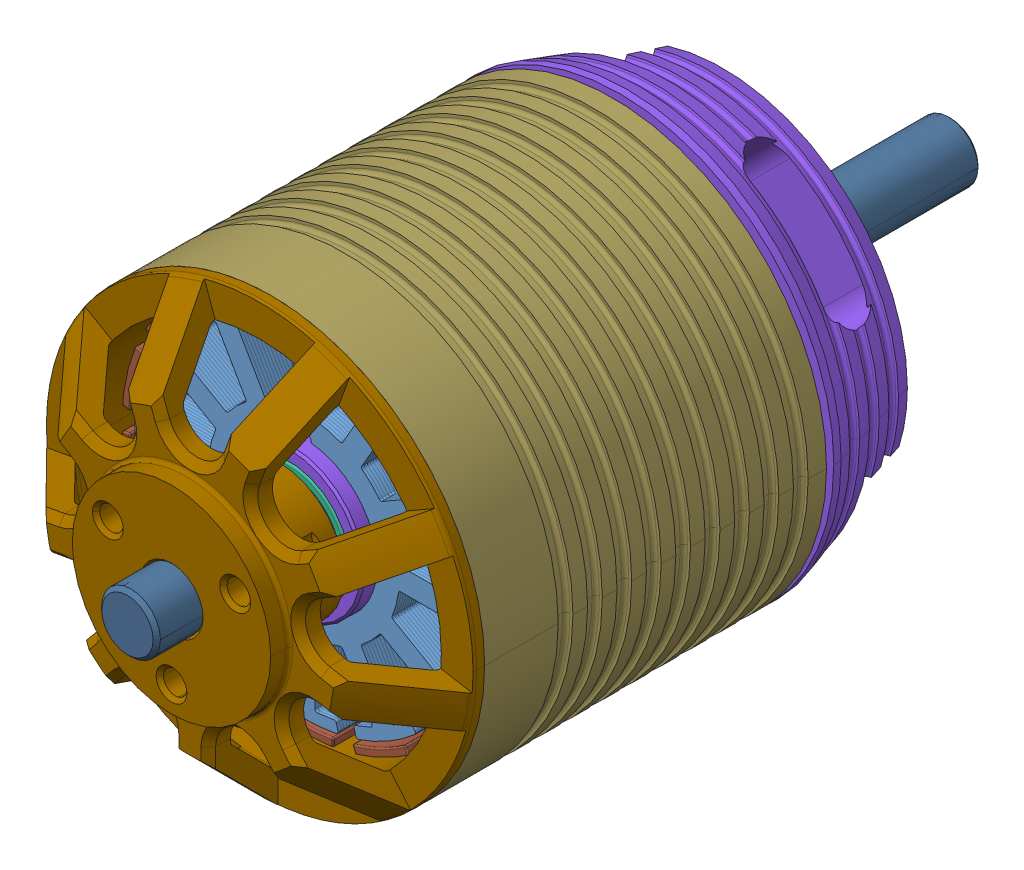
SolidWorks assembly BA-2320-Motor, configuration Default. Lengths in mm.
Overall size (29.1 29.1 56).
158 component instances, 15 part files, 0 mates.
Components (placement in the parent):
- 2320-Stator-Assem.STEP-1: 2320-Stator-Assem.STEP [Default] at (54.7125 -14.0588 -19.3197) size (29.1 29.1 29.5)
  - 23x10x20mm-Stator.STEP-1: 23x10x20mm-Stator.STEP [Default] at (-19.0817 6.8885 -13.7) size (23 23 20)
    - 23x10x15mm-Stator.STEP-1: 23x10x15mm-Stator.STEP [Default] at (56.8774 -9.8625 7.0262) size (23 23 15)
      - 23x10x5mm-Stator.STEP-1: 23x10x5mm-Stator.STEP [Default] at (-13.8317 15.0051 -0.8954) size (23 23 5)
        - 23x10x1mm-Stator.STEP-1: 23x10x1mm-Stator.STEP [Default] at (-15.1244 2.7036 6.5442) size (23 23 1)
          - 23x10-Stator-Plate.STEP-1: 23x10-Stator-Plate.STEP [Default] at (-25.8459 0.0676 13.4926) size (23 23 0.2)
          - 23x10-Stator-Plate.STEP-2: 23x10-Stator-Plate.STEP [Default] at (-25.8459 0.0676 13.2926) size (23 23 0.2)
          - 23x10-Stator-Plate.STEP-3: 23x10-Stator-Plate.STEP [Default] at (-25.8459 0.0676 13.0926) size (23 23 0.2)
          - 23x10-Stator-Plate.STEP-4: 23x10-Stator-Plate.STEP [Default] at (-25.8459 0.0676 12.8926) size (23 23 0.2)
          - 23x10-Stator-Plate.STEP-5: 23x10-Stator-Plate.STEP [Default] at (-25.8459 0.0676 12.6926) size (23 23 0.2)
        - 23x10x1mm-Stator.STEP-2: 23x10x1mm-Stator.STEP [Default] at (-15.1244 2.7036 5.5442) size (23 23 1)
          - 23x10-Stator-Plate.STEP-1: 23x10-Stator-Plate.STEP [Default] at (-25.8459 0.0676 13.4926) size (23 23 0.2)
          - 23x10-Stator-Plate.STEP-2: 23x10-Stator-Plate.STEP [Default] at (-25.8459 0.0676 13.2926) size (23 23 0.2)
          - 23x10-Stator-Plate.STEP-3: 23x10-Stator-Plate.STEP [Default] at (-25.8459 0.0676 13.0926) size (23 23 0.2)
          - 23x10-Stator-Plate.STEP-4: 23x10-Stator-Plate.STEP [Default] at (-25.8459 0.0676 12.8926) size (23 23 0.2)
          - 23x10-Stator-Plate.STEP-5: 23x10-Stator-Plate.STEP [Default] at (-25.8459 0.0676 12.6926) size (23 23 0.2)
        - 23x10x1mm-Stator.STEP-3: 23x10x1mm-Stator.STEP [Default] at (-15.1244 2.7036 4.5442) size (23 23 1)
          - 23x10-Stator-Plate.STEP-1: 23x10-Stator-Plate.STEP [Default] at (-25.8459 0.0676 13.4926) size (23 23 0.2)
          - 23x10-Stator-Plate.STEP-2: 23x10-Stator-Plate.STEP [Default] at (-25.8459 0.0676 13.2926) size (23 23 0.2)
          - 23x10-Stator-Plate.STEP-3: 23x10-Stator-Plate.STEP [Default] at (-25.8459 0.0676 13.0926) size (23 23 0.2)
          - 23x10-Stator-Plate.STEP-4: 23x10-Stator-Plate.STEP [Default] at (-25.8459 0.0676 12.8926) size (23 23 0.2)
          - 23x10-Stator-Plate.STEP-5: 23x10-Stator-Plate.STEP [Default] at (-25.8459 0.0676 12.6926) size (23 23 0.2)
        - 23x10x1mm-Stator.STEP-4: 23x10x1mm-Stator.STEP [Default] at (-15.1244 2.7036 3.5442) size (23 23 1)
          - 23x10-Stator-Plate.STEP-1: 23x10-Stator-Plate.STEP [Default] at (-25.8459 0.0676 13.4926) size (23 23 0.2)
          - 23x10-Stator-Plate.STEP-2: 23x10-Stator-Plate.STEP [Default] at (-25.8459 0.0676 13.2926) size (23 23 0.2)
          - 23x10-Stator-Plate.STEP-3: 23x10-Stator-Plate.STEP [Default] at (-25.8459 0.0676 13.0926) size (23 23 0.2)
          - 23x10-Stator-Plate.STEP-4: 23x10-Stator-Plate.STEP [Default] at (-25.8459 0.0676 12.8926) size (23 23 0.2)
          - 23x10-Stator-Plate.STEP-5: 23x10-Stator-Plate.STEP [Default] at (-25.8459 0.0676 12.6926) size (23 23 0.2)
        - 23x10x1mm-Stator.STEP-5: 23x10x1mm-Stator.STEP [Default] at (-15.1244 2.7036 2.5442) size (23 23 1)
          - 23x10-Stator-Plate.STEP-1: 23x10-Stator-Plate.STEP [Default] at (-25.8459 0.0676 13.4926) size (23 23 0.2)
          - 23x10-Stator-Plate.STEP-2: 23x10-Stator-Plate.STEP [Default] at (-25.8459 0.0676 13.2926) size (23 23 0.2)
          - 23x10-Stator-Plate.STEP-3: 23x10-Stator-Plate.STEP [Default] at (-25.8459 0.0676 13.0926) size (23 23 0.2)
          - 23x10-Stator-Plate.STEP-4: 23x10-Stator-Plate.STEP [Default] at (-25.8459 0.0676 12.8926) size (23 23 0.2)
          - 23x10-Stator-Plate.STEP-5: 23x10-Stator-Plate.STEP [Default] at (-25.8459 0.0676 12.6926) size (23 23 0.2)
      - 23x10x5mm-Stator.STEP-2: 23x10x5mm-Stator.STEP [Default] at (-13.8317 15.0051 -5.8954) size (23 23 5)
        - 23x10x1mm-Stator.STEP-1: 23x10x1mm-Stator.STEP [Default] at (-15.1244 2.7036 6.5442) size (23 23 1)
          - 23x10-Stator-Plate.STEP-1: 23x10-Stator-Plate.STEP [Default] at (-25.8459 0.0676 13.4926) size (23 23 0.2)
          - 23x10-Stator-Plate.STEP-2: 23x10-Stator-Plate.STEP [Default] at (-25.8459 0.0676 13.2926) size (23 23 0.2)
          - 23x10-Stator-Plate.STEP-3: 23x10-Stator-Plate.STEP [Default] at (-25.8459 0.0676 13.0926) size (23 23 0.2)
          - 23x10-Stator-Plate.STEP-4: 23x10-Stator-Plate.STEP [Default] at (-25.8459 0.0676 12.8926) size (23 23 0.2)
          - 23x10-Stator-Plate.STEP-5: 23x10-Stator-Plate.STEP [Default] at (-25.8459 0.0676 12.6926) size (23 23 0.2)
        - 23x10x1mm-Stator.STEP-2: 23x10x1mm-Stator.STEP [Default] at (-15.1244 2.7036 5.5442) size (23 23 1)
          - 23x10-Stator-Plate.STEP-1: 23x10-Stator-Plate.STEP [Default] at (-25.8459 0.0676 13.4926) size (23 23 0.2)
          - 23x10-Stator-Plate.STEP-2: 23x10-Stator-Plate.STEP [Default] at (-25.8459 0.0676 13.2926) size (23 23 0.2)
          - 23x10-Stator-Plate.STEP-3: 23x10-Stator-Plate.STEP [Default] at (-25.8459 0.0676 13.0926) size (23 23 0.2)
          - 23x10-Stator-Plate.STEP-4: 23x10-Stator-Plate.STEP [Default] at (-25.8459 0.0676 12.8926) size (23 23 0.2)
          - 23x10-Stator-Plate.STEP-5: 23x10-Stator-Plate.STEP [Default] at (-25.8459 0.0676 12.6926) size (23 23 0.2)
        - 23x10x1mm-Stator.STEP-3: 23x10x1mm-Stator.STEP [Default] at (-15.1244 2.7036 4.5442) size (23 23 1)
          - 23x10-Stator-Plate.STEP-1: 23x10-Stator-Plate.STEP [Default] at (-25.8459 0.0676 13.4926) size (23 23 0.2)
          - 23x10-Stator-Plate.STEP-2: 23x10-Stator-Plate.STEP [Default] at (-25.8459 0.0676 13.2926) size (23 23 0.2)
          - 23x10-Stator-Plate.STEP-3: 23x10-Stator-Plate.STEP [Default] at (-25.8459 0.0676 13.0926) size (23 23 0.2)
          - 23x10-Stator-Plate.STEP-4: 23x10-Stator-Plate.STEP [Default] at (-25.8459 0.0676 12.8926) size (23 23 0.2)
          - 23x10-Stator-Plate.STEP-5: 23x10-Stator-Plate.STEP [Default] at (-25.8459 0.0676 12.6926) size (23 23 0.2)
        - 23x10x1mm-Stator.STEP-4: 23x10x1mm-Stator.STEP [Default] at (-15.1244 2.7036 3.5442) size (23 23 1)
          - 23x10-Stator-Plate.STEP-1: 23x10-Stator-Plate.STEP [Default] at (-25.8459 0.0676 13.4926) size (23 23 0.2)
          - 23x10-Stator-Plate.STEP-2: 23x10-Stator-Plate.STEP [Default] at (-25.8459 0.0676 13.2926) size (23 23 0.2)
          - 23x10-Stator-Plate.STEP-3: 23x10-Stator-Plate.STEP [Default] at (-25.8459 0.0676 13.0926) size (23 23 0.2)
          - 23x10-Stator-Plate.STEP-4: 23x10-Stator-Plate.STEP [Default] at (-25.8459 0.0676 12.8926) size (23 23 0.2)
          - 23x10-Stator-Plate.STEP-5: 23x10-Stator-Plate.STEP [Default] at (-25.8459 0.0676 12.6926) size (23 23 0.2)
        - 23x10x1mm-Stator.STEP-5: 23x10x1mm-Stator.STEP [Default] at (-15.1244 2.7036 2.5442) size (23 23 1)
          - 23x10-Stator-Plate.STEP-1: 23x10-Stator-Plate.STEP [Default] at (-25.8459 0.0676 13.4926) size (23 23 0.2)
          - 23x10-Stator-Plate.STEP-2: 23x10-Stator-Plate.STEP [Default] at (-25.8459 0.0676 13.2926) size (23 23 0.2)
          - 23x10-Stator-Plate.STEP-3: 23x10-Stator-Plate.STEP [Default] at (-25.8459 0.0676 13.0926) size (23 23 0.2)
          - 23x10-Stator-Plate.STEP-4: 23x10-Stator-Plate.STEP [Default] at (-25.8459 0.0676 12.8926) size (23 23 0.2)
          - 23x10-Stator-Plate.STEP-5: 23x10-Stator-Plate.STEP [Default] at (-25.8459 0.0676 12.6926) size (23 23 0.2)
      - 23x10x5mm-Stator.STEP-3: 23x10x5mm-Stator.STEP [Default] at (-13.8317 15.0051 -10.8954) size (23 23 5)
        - 23x10x1mm-Stator.STEP-1: 23x10x1mm-Stator.STEP [Default] at (-15.1244 2.7036 6.5442) size (23 23 1)
          - 23x10-Stator-Plate.STEP-1: 23x10-Stator-Plate.STEP [Default] at (-25.8459 0.0676 13.4926) size (23 23 0.2)
          - 23x10-Stator-Plate.STEP-2: 23x10-Stator-Plate.STEP [Default] at (-25.8459 0.0676 13.2926) size (23 23 0.2)
          - 23x10-Stator-Plate.STEP-3: 23x10-Stator-Plate.STEP [Default] at (-25.8459 0.0676 13.0926) size (23 23 0.2)
          - 23x10-Stator-Plate.STEP-4: 23x10-Stator-Plate.STEP [Default] at (-25.8459 0.0676 12.8926) size (23 23 0.2)
          - 23x10-Stator-Plate.STEP-5: 23x10-Stator-Plate.STEP [Default] at (-25.8459 0.0676 12.6926) size (23 23 0.2)
        - 23x10x1mm-Stator.STEP-2: 23x10x1mm-Stator.STEP [Default] at (-15.1244 2.7036 5.5442) size (23 23 1)
          - 23x10-Stator-Plate.STEP-1: 23x10-Stator-Plate.STEP [Default] at (-25.8459 0.0676 13.4926) size (23 23 0.2)
          - 23x10-Stator-Plate.STEP-2: 23x10-Stator-Plate.STEP [Default] at (-25.8459 0.0676 13.2926) size (23 23 0.2)
          - 23x10-Stator-Plate.STEP-3: 23x10-Stator-Plate.STEP [Default] at (-25.8459 0.0676 13.0926) size (23 23 0.2)
          - 23x10-Stator-Plate.STEP-4: 23x10-Stator-Plate.STEP [Default] at (-25.8459 0.0676 12.8926) size (23 23 0.2)
          - 23x10-Stator-Plate.STEP-5: 23x10-Stator-Plate.STEP [Default] at (-25.8459 0.0676 12.6926) size (23 23 0.2)
        - 23x10x1mm-Stator.STEP-3: 23x10x1mm-Stator.STEP [Default] at (-15.1244 2.7036 4.5442) size (23 23 1)
          - 23x10-Stator-Plate.STEP-1: 23x10-Stator-Plate.STEP [Default] at (-25.8459 0.0676 13.4926) size (23 23 0.2)
          - 23x10-Stator-Plate.STEP-2: 23x10-Stator-Plate.STEP [Default] at (-25.8459 0.0676 13.2926) size (23 23 0.2)
          - 23x10-Stator-Plate.STEP-3: 23x10-Stator-Plate.STEP [Default] at (-25.8459 0.0676 13.0926) size (23 23 0.2)
          - 23x10-Stator-Plate.STEP-4: 23x10-Stator-Plate.STEP [Default] at (-25.8459 0.0676 12.8926) size (23 23 0.2)
          - 23x10-Stator-Plate.STEP-5: 23x10-Stator-Plate.STEP [Default] at (-25.8459 0.0676 12.6926) size (23 23 0.2)
        - 23x10x1mm-Stator.STEP-4: 23x10x1mm-Stator.STEP [Default] at (-15.1244 2.7036 3.5442) size (23 23 1)
          - 23x10-Stator-Plate.STEP-1: 23x10-Stator-Plate.STEP [Default] at (-25.8459 0.0676 13.4926) size (23 23 0.2)
          - 23x10-Stator-Plate.STEP-2: 23x10-Stator-Plate.STEP [Default] at (-25.8459 0.0676 13.2926) size (23 23 0.2)
          - 23x10-Stator-Plate.STEP-3: 23x10-Stator-Plate.STEP [Default] at (-25.8459 0.0676 13.0926) size (23 23 0.2)
          - 23x10-Stator-Plate.STEP-4: 23x10-Stator-Plate.STEP [Default] at (-25.8459 0.0676 12.8926) size (23 23 0.2)
          - 23x10-Stator-Plate.STEP-5: 23x10-Stator-Plate.STEP [Default] at (-25.8459 0.0676 12.6926) size (23 23 0.2)
        - 23x10x1mm-Stator.STEP-5: 23x10x1mm-Stator.STEP [Default] at (-15.1244 2.7036 2.5442) size (23 23 1)
          - 23x10-Stator-Plate.STEP-1: 23x10-Stator-Plate.STEP [Default] at (-25.8459 0.0676 13.4926) size (23 23 0.2)
          - 23x10-Stator-Plate.STEP-2: 23x10-Stator-Plate.STEP [Default] at (-25.8459 0.0676 13.2926) size (23 23 0.2)
          - 23x10-Stator-Plate.STEP-3: 23x10-Stator-Plate.STEP [Default] at (-25.8459 0.0676 13.0926) size (23 23 0.2)
          - 23x10-Stator-Plate.STEP-4: 23x10-Stator-Plate.STEP [Default] at (-25.8459 0.0676 12.8926) size (23 23 0.2)
          - 23x10-Stator-Plate.STEP-5: 23x10-Stator-Plate.STEP [Default] at (-25.8459 0.0676 12.6926) size (23 23 0.2)
    - 23x10x5mm-Stator.STEP-1: 23x10x5mm-Stator.STEP [Default] at (43.0457 5.1426 -8.8692) size (23 23 5)
      - 23x10x1mm-Stator.STEP-1: 23x10x1mm-Stator.STEP [Default] at (-15.1244 2.7036 6.5442) size (23 23 1)
        - 23x10-Stator-Plate.STEP-1: 23x10-Stator-Plate.STEP [Default] at (-25.8459 0.0676 13.4926) size (23 23 0.2)
        - 23x10-Stator-Plate.STEP-2: 23x10-Stator-Plate.STEP [Default] at (-25.8459 0.0676 13.2926) size (23 23 0.2)
        - 23x10-Stator-Plate.STEP-3: 23x10-Stator-Plate.STEP [Default] at (-25.8459 0.0676 13.0926) size (23 23 0.2)
        - 23x10-Stator-Plate.STEP-4: 23x10-Stator-Plate.STEP [Default] at (-25.8459 0.0676 12.8926) size (23 23 0.2)
        - 23x10-Stator-Plate.STEP-5: 23x10-Stator-Plate.STEP [Default] at (-25.8459 0.0676 12.6926) size (23 23 0.2)
      - 23x10x1mm-Stator.STEP-2: 23x10x1mm-Stator.STEP [Default] at (-15.1244 2.7036 5.5442) size (23 23 1)
        - 23x10-Stator-Plate.STEP-1: 23x10-Stator-Plate.STEP [Default] at (-25.8459 0.0676 13.4926) size (23 23 0.2)
        - 23x10-Stator-Plate.STEP-2: 23x10-Stator-Plate.STEP [Default] at (-25.8459 0.0676 13.2926) size (23 23 0.2)
        - 23x10-Stator-Plate.STEP-3: 23x10-Stator-Plate.STEP [Default] at (-25.8459 0.0676 13.0926) size (23 23 0.2)
        - 23x10-Stator-Plate.STEP-4: 23x10-Stator-Plate.STEP [Default] at (-25.8459 0.0676 12.8926) size (23 23 0.2)
        - 23x10-Stator-Plate.STEP-5: 23x10-Stator-Plate.STEP [Default] at (-25.8459 0.0676 12.6926) size (23 23 0.2)
      - 23x10x1mm-Stator.STEP-3: 23x10x1mm-Stator.STEP [Default] at (-15.1244 2.7036 4.5442) size (23 23 1)
        - 23x10-Stator-Plate.STEP-1: 23x10-Stator-Plate.STEP [Default] at (-25.8459 0.0676 13.4926) size (23 23 0.2)
        - 23x10-Stator-Plate.STEP-2: 23x10-Stator-Plate.STEP [Default] at (-25.8459 0.0676 13.2926) size (23 23 0.2)
        - 23x10-Stator-Plate.STEP-3: 23x10-Stator-Plate.STEP [Default] at (-25.8459 0.0676 13.0926) size (23 23 0.2)
        - 23x10-Stator-Plate.STEP-4: 23x10-Stator-Plate.STEP [Default] at (-25.8459 0.0676 12.8926) size (23 23 0.2)
        - 23x10-Stator-Plate.STEP-5: 23x10-Stator-Plate.STEP [Default] at (-25.8459 0.0676 12.6926) size (23 23 0.2)
      - 23x10x1mm-Stator.STEP-4: 23x10x1mm-Stator.STEP [Default] at (-15.1244 2.7036 3.5442) size (23 23 1)
        - 23x10-Stator-Plate.STEP-1: 23x10-Stator-Plate.STEP [Default] at (-25.8459 0.0676 13.4926) size (23 23 0.2)
        - 23x10-Stator-Plate.STEP-2: 23x10-Stator-Plate.STEP [Default] at (-25.8459 0.0676 13.2926) size (23 23 0.2)
        - 23x10-Stator-Plate.STEP-3: 23x10-Stator-Plate.STEP [Default] at (-25.8459 0.0676 13.0926) size (23 23 0.2)
        - 23x10-Stator-Plate.STEP-4: 23x10-Stator-Plate.STEP [Default] at (-25.8459 0.0676 12.8926) size (23 23 0.2)
        - 23x10-Stator-Plate.STEP-5: 23x10-Stator-Plate.STEP [Default] at (-25.8459 0.0676 12.6926) size (23 23 0.2)
      - 23x10x1mm-Stator.STEP-5: 23x10x1mm-Stator.STEP [Default] at (-15.1244 2.7036 2.5442) size (23 23 1)
        - 23x10-Stator-Plate.STEP-1: 23x10-Stator-Plate.STEP [Default] at (-25.8459 0.0676 13.4926) size (23 23 0.2)
        - 23x10-Stator-Plate.STEP-2: 23x10-Stator-Plate.STEP [Default] at (-25.8459 0.0676 13.2926) size (23 23 0.2)
        - 23x10-Stator-Plate.STEP-3: 23x10-Stator-Plate.STEP [Default] at (-25.8459 0.0676 13.0926) size (23 23 0.2)
        - 23x10-Stator-Plate.STEP-4: 23x10-Stator-Plate.STEP [Default] at (-25.8459 0.0676 12.8926) size (23 23 0.2)
        - 23x10-Stator-Plate.STEP-5: 23x10-Stator-Plate.STEP [Default] at (-25.8459 0.0676 12.6926) size (23 23 0.2)
  - 4x11x4-BRG.STEP-1: 4x11x4-BRG.STEP [Default] at (-17.0063 14.8023 -13.3264) x (0 0 1) z (-0.99991 0.013404 0) size (3.99 11 11)
    - 694HZZ_SOLID_1-1.STEP-1: 694HZZ_SOLID_1-1.STEP [Default] at origin size (3.99 6.18 6.18)
    - 694HZZ_SOLID_2-1.STEP-1: 694HZZ_SOLID_2-1.STEP [Default] at origin size (3.99 11 11)
    - 694HZZ_SOLID_3-1.STEP-1: 694HZZ_SOLID_3-1.STEP [Default] at origin size (2.34 9.37 9.37)
  - 4x8x3-BRG.STEP-1: 4x8x3-BRG.STEP [Default] at (-17.0063 14.8023 12.1661) x (0 0 -1) z (0.978029 0.208467 0) size (3 8 8)
    - SMR84ZZ_SOLID_1.STEP-1: SMR84ZZ_SOLID_1.STEP [Default] at origin size (3 5.01 5.01)
    - SMR84ZZ_SOLID_2.STEP-1: SMR84ZZ_SOLID_2.STEP [Default] at origin size (3 8 8)
    - SMR84ZZ_SOLID_3.STEP-1: SMR84ZZ_SOLID_3.STEP [Default] at origin size (1.76 7.4 7.4)
  - 2320-Mount.STEP-1: 2320-Mount.STEP [Default] at (-17.0063 14.8023 -15.8325) size (29.1 29.1 29.5)
- 2320-Rotor-Assem.STEP-1: 2320-Rotor-Assem.STEP [Default] at (77.3488 -11.22 -17.321) size (29.1 29.1 56)
  - 23mm-Endbell.STEP-1: 23mm-Endbell.STEP [Default] at (-39.6426 11.9635 6.916) size (29.1 29.1 12.75)
  - 2320-Shaft.STEP-1: 2320-Shaft.STEP [Default] at (-39.6426 11.9635 -33.334) size (4 4 56)
  - 2320-Magnet.STEP-1: 2320-Magnet.STEP [Default] at (-39.6426 11.9635 -9.334) size (4 1.65 20)
  - 2320-Magnet.STEP-2: 2320-Magnet.STEP [Default] at (-39.6426 11.9635 -9.334) x (0.900969 0.433884 0) z (0 0 1) size (4 1.65 20)
  - 2320-Magnet.STEP-3: 2320-Magnet.STEP [Default] at (-39.6426 11.9635 -9.334) x (0.62349 0.781831 0) z (0 0 1) size (4 1.65 20)
  - 2320-Magnet.STEP-4: 2320-Magnet.STEP [Default] at (-39.6426 11.9635 -9.334) x (0.222521 0.974928 0) z (0 0 1) size (4 1.65 20)
  - 2320-Magnet.STEP-5: 2320-Magnet.STEP [Default] at (-39.6426 11.9635 -9.334) x (-0.222521 0.974928 0) z (0 0 1) size (4 1.65 20)
  - 2320-Magnet.STEP-6: 2320-Magnet.STEP [Default] at (-39.6426 11.9635 -9.334) x (-0.62349 0.781831 0) z (0 0 1) size (4 1.65 20)
  - 2320-Magnet.STEP-7: 2320-Magnet.STEP [Default] at (-39.6426 11.9635 -9.334) x (-0.900969 0.433884 0) z (0 0 1) size (4 1.65 20)
  - 2320-Magnet.STEP-8: 2320-Magnet.STEP [Default] at (-39.6426 11.9635 -9.334) x (-1 0 0) z (0 0 1) size (4 1.65 20)
  - 2320-Magnet.STEP-9: 2320-Magnet.STEP [Default] at (-39.6426 11.9635 -9.334) x (-0.900969 -0.433884 0) z (0 0 1) size (4 1.65 20)
  - 2320-Magnet.STEP-10: 2320-Magnet.STEP [Default] at (-39.6426 11.9635 -9.334) x (-0.62349 -0.781831 0) z (0 0 1) size (4 1.65 20)
  - 2320-Magnet.STEP-11: 2320-Magnet.STEP [Default] at (-39.6426 11.9635 -9.334) x (-0.222521 -0.974928 0) z (0 0 1) size (4 1.65 20)
  - 2320-Magnet.STEP-12: 2320-Magnet.STEP [Default] at (-39.6426 11.9635 -9.334) x (0.222521 -0.974928 0) z (0 0 1) size (4 1.65 20)
  - 2320-Magnet.STEP-13: 2320-Magnet.STEP [Default] at (-39.6426 11.9635 -9.334) x (0.62349 -0.781831 0) z (0 0 1) size (4 1.65 20)
  - 2320-Magnet.STEP-14: 2320-Magnet.STEP [Default] at (-39.6426 11.9635 -9.334) x (0.900969 -0.433884 0) z (0 0 1) size (4 1.65 20)
  - 2320-Fluxring.STEP-1: 2320-Fluxring.STEP [Default] at (-39.6426 11.9635 -10.334) size (29.1 29.1 23.25)
- Spacer-4mm.STEP-1: Spacer-4mm.STEP [Default] at (37.7062 0.7435 -5.655) size (6 6 0.25)
- Spacer-4mm.STEP-2: Spacer-4mm.STEP [Default] at (37.7062 0.7435 -34.89) size (6 6 0.25)
- Collar-4mm.STEP-1: Collar-4mm.STEP [Default] at (37.7062 0.7435 -40.305) x (-0.170561 0.985347 0) z (0 0 1) size (8.5 8.5 5)
- C-Clip-4mm_98541A112.STEP-1: C-Clip-4mm_98541A112.STEP [Default] at (37.7062 0.7435 -35.105) x (0 0 -1) z (-0.978839 0.20463 0) size (0.4 6.8 5.16)
